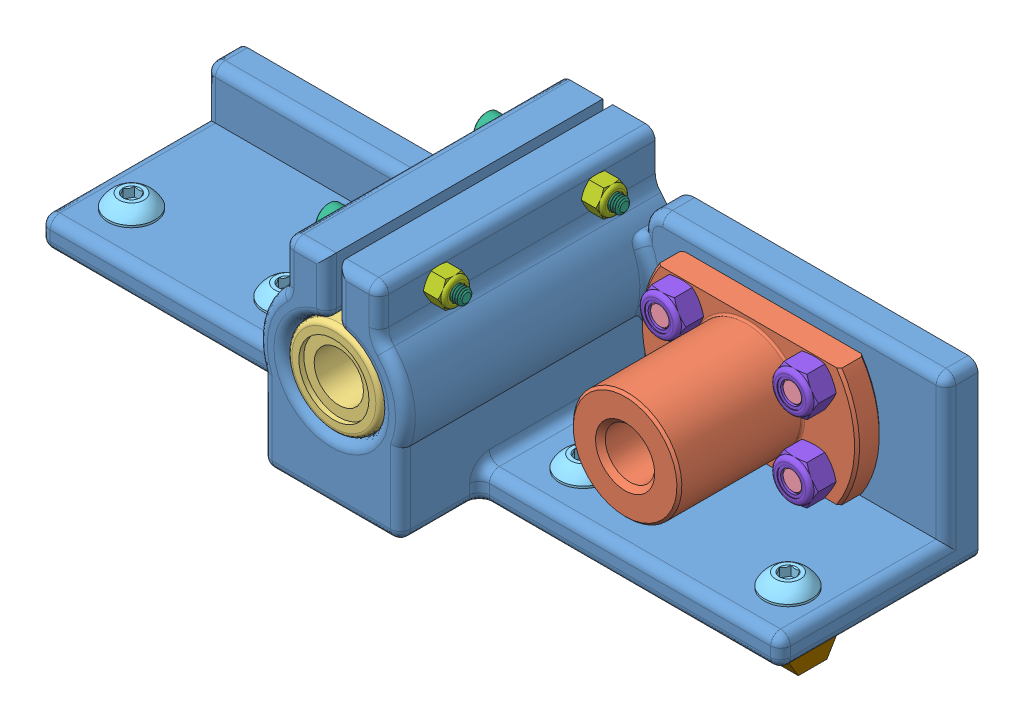
SolidWorks assembly Z_Axis_Bed_Support, configuration Default. Lengths in mm.
Overall size (150 48.5 58.92).
23 component instances, 9 part files, 65 mates.
Components (placement in the parent):
- Z_Axis_Bed_Support-1: Z_Axis_Bed_Support [Default] at origin size (150 43 56)
- MTSGR12-1: MTSGR12 [Default] at (-35 19 6.5) x (0 0 1) z (0 -1 0) size (30 44 24)
- LM10LUU-1: LM10LUU [Default] at (-75 22 0.5) size (19 19 55)
- 5mmX16mm_Buttonhead(McMaster_91239A232)-5: 5mmX16mm_Buttonhead(McMaster_91239A232) [91239A232] at (-48.423 11.25 -2.75) x (0.866025 0.5 0) z (0 0 -1) size (9.5 9.5 19.24)
- 5mmX16mm_Buttonhead(McMaster_91239A232)-7: 5mmX16mm_Buttonhead(McMaster_91239A232) [91239A232] at (-21.577 11.25 -2.75) x (0.866025 0.5 0) z (0 0 -1) size (9.5 9.5 19.24)
- 5mmX16mm_Buttonhead(McMaster_91239A232)-6: 5mmX16mm_Buttonhead(McMaster_91239A232) [91239A232] at (-48.423 26.75 -2.75) x (0.866025 -0.5 0) z (0 0 -1) size (9.5 9.5 19.24)
- 5mmX16mm_Buttonhead(McMaster_91239A232)-4: 5mmX16mm_Buttonhead(McMaster_91239A232) [91239A232] at (-21.577 26.75 -2.75) x (0.866025 -0.5 0) z (0 0 -1) size (9.5 9.5 19.24)
- 5mmX10mm_Buttonhead(McMaster_91239A224)-7: 5mmX10mm_Buttonhead(McMaster_91239A224) [91239A224] at (-8.5 8.75 30) x (0 0 -1) z (0 1 0) size (9.5 9.5 13.21)
- 5mmX10mm_Buttonhead(McMaster_91239A224)-6: 5mmX10mm_Buttonhead(McMaster_91239A224) [91239A224] at (-50 8.75 30) x (0.866025 0 -0.5) z (0 1 0) size (9.5 9.5 13.21)
- 5mmX10mm_Buttonhead(McMaster_91239A224)-8: 5mmX10mm_Buttonhead(McMaster_91239A224) [91239A224] at (-110 8.75 30) x (-0.866025 0 0.5) z (0 1 0) size (9.5 9.5 13.21)
- 5mmX10mm_Buttonhead(McMaster_91239A224)-9: 5mmX10mm_Buttonhead(McMaster_91239A224) [91239A224] at (-141.5 8.75 30) x (-0.866025 0 0.5) z (0 1 0) size (9.5 9.5 13.21)
- 3mmX25mm_Sockethead(McMaster_91290A125)-4: 3mmX25mm_Sockethead(McMaster_91290A125) [91290A125] at (-59.6 38.2628 12) x (0 0 -1) z (1 0 0) size (5.5 5.5 28.26)
- 3mmX25mm_Sockethead(McMaster_91290A125)-3: 3mmX25mm_Sockethead(McMaster_91290A125) [91290A125] at (-59.6 38.2628 44) x (0 0 -1) z (1 0 0) size (5.5 5.5 28.26)
- 3mm_Hex_Nylock_Nut(McMaster_90576A102)-3: 3mm_Hex_Nylock_Nut(McMaster_90576A102) [90576A102] at (-65.4 38.2628 12) x (0 1 0) z (0 0 -1) size (5.5 4.1 6.35)
- 3mm_Hex_Nylock_Nut(McMaster_90576A102)-2: 3mm_Hex_Nylock_Nut(McMaster_90576A102) [90576A102] at (-65.4 38.2628 44) x (0 0.5 0.866025) z (0 0.866025 -0.5) size (5.5 4.1 6.35)
- 5mm_Hex_NyLockNut(McMaster_94205A240)-5: 5mm_Hex_NyLockNut(McMaster_94205A240) [94205A240] at (-21.577 26.75 11.5) x (0.866025 -0.5 0) z (-0.5 -0.866025 0) size (8 5.15 9.24)
- 5mm_Hex_NyLockNut(McMaster_94205A240)-7: 5mm_Hex_NyLockNut(McMaster_94205A240) [94205A240] at (-48.423 26.75 11.5) x (0.866025 -0.5 0) z (-0.5 -0.866025 0) size (8 5.15 9.24)
- 5mm_Hex_NyLockNut(McMaster_94205A240)-6: 5mm_Hex_NyLockNut(McMaster_94205A240) [94205A240] at (-21.577 11.25 11.5) x (0.866025 0.5 0) z (0.5 -0.866025 0) size (8 5.15 9.24)
- 5mm_Hex_NyLockNut(McMaster_94205A240)-4: 5mm_Hex_NyLockNut(McMaster_94205A240) [94205A240] at (-48.423 11.25 11.5) x (-0.866025 -0.5 0) z (-0.5 0.866025 0) size (8 5.15 9.24)
- HNTTSN5-5-1: HNTTSN5-5 [Default] at (-50 -1.2 30) x (0 1 0) z (-1 0 0) size (4.3 10 10)
- HNTTSN5-5-2: HNTTSN5-5 [Default] at (-110 -1.2 30) x (0 1 0) z (1 0 0) size (4.3 10 10)
- HNTTSN5-5-3: HNTTSN5-5 [Default] at (-8.5 -1.2 30) x (0 1 0) z (1 0 0) size (4.3 10 10)
- HNTTSN5-5-4: HNTTSN5-5 [Default] at (-141.5 -1.2 30) x (0 1 0) z (1 0 0) size (4.3 10 10)
Mates (geometry in assembly coordinates):
- Concentric1: concentric aligned: cylinder of Z_Axis_Bed_Support-1 through (-75 22 6.5) axis (0 0 -1) radius 9.65; cylinder of LM10LUU-1 through (-75 22 55.5) axis (0 0 -1) radius 9.5
- Distance1: distance = 0.5 mm aligned: plane of LM10LUU-1 through (-75 22 0.5) normal (0 0 -1); plane of Z_Axis_Bed_Support-1 through (0 6 0) normal (0 0 -1)
- Coincident2: coincident anti-aligned: plane of Z_Axis_Bed_Support-1 through (-57.4 31 6.5) normal (0 0 1); plane of MTSGR12-1 through (-35 19 6.5) normal (0 0 -1)
- Parallel2: parallel aligned: plane of Z_Axis_Bed_Support-1 through (-74 43 6.5) normal (0 1 0); plane of MTSGR12-1 through (9 31 14) normal (0 1 0)
- Concentric4: concentric aligned: cylinder of Z_Axis_Bed_Support-1 through (-35 19 6.5) axis (0 0 -1) radius 7.15; cylinder of MTSGR12-1 through (-35 19 36.5) axis (0 0 -1) radius 5
- Concentric51: concentric aligned: cylinder of Z_Axis_Bed_Support-1 through (-48.423 11.25 6.5) axis (0 0 -1) radius 2.6; cylinder of 5mmX16mm_Buttonhead(McMaster_91239A232)-5 through (-48.423 11.25 -2.75) axis (0 0 -1) radius 4.75
- Coincident31: coincident anti-aligned: plane of Z_Axis_Bed_Support-1 through (0 6 0) normal (0 0 -1); plane of 5mmX16mm_Buttonhead(McMaster_91239A232)-5 through (-50.798 15.3636 0) normal (0 0 1)
- Concentric61: concentric aligned: cylinder of Z_Axis_Bed_Support-1 through (-21.577 11.25 6.5) axis (0 0 -1) radius 2.6; cylinder of 5mmX16mm_Buttonhead(McMaster_91239A232)-7 through (-21.577 11.25 -2.75) axis (0 0 -1) radius 4.75
- Coincident41: coincident anti-aligned: plane of Z_Axis_Bed_Support-1 through (0 6 0) normal (0 0 -1); plane of 5mmX16mm_Buttonhead(McMaster_91239A232)-7 through (-23.952 15.3636 0) normal (0 0 1)
- Concentric71: concentric aligned: cylinder of Z_Axis_Bed_Support-1 through (-48.423 26.75 6.5) axis (0 0 -1) radius 2.6; cylinder of 5mmX16mm_Buttonhead(McMaster_91239A232)-6 through (-48.423 26.75 -2.75) axis (0 0 -1) radius 4.75
- Coincident51: coincident anti-aligned: plane of Z_Axis_Bed_Support-1 through (0 6 0) normal (0 0 -1); plane of 5mmX16mm_Buttonhead(McMaster_91239A232)-6 through (-46.048 30.8636 0) normal (0 0 1)
- Concentric81: concentric aligned: cylinder of Z_Axis_Bed_Support-1 through (-21.577 26.75 6.5) axis (0 0 -1) radius 2.6; cylinder of 5mmX16mm_Buttonhead(McMaster_91239A232)-4 through (-21.577 26.75 -2.75) axis (0 0 -1) radius 4.75
- Coincident61: coincident anti-aligned: plane of Z_Axis_Bed_Support-1 through (0 6 0) normal (0 0 -1); plane of 5mmX16mm_Buttonhead(McMaster_91239A232)-4 through (-19.202 30.8636 0) normal (0 0 1)
- Concentric9: concentric aligned: cylinder of 5mmX16mm_Buttonhead(McMaster_91239A232)-4 through (-21.577 26.75 -2.75) axis (0 0 -1) radius 4.75; cylinder of 5mm_Hex_NyLockNut(McMaster_94205A240)-5 through (-21.577 26.75 15.7429) axis (0 0 -1) radius 2.1277
- Coincident7: coincident anti-aligned: plane of MTSGR12-1 through (-56.5 19 11.5) normal (0 0 1); plane of 5mm_Hex_NyLockNut(McMaster_94205A240)-5 through (-21.577 34.75 11.5) normal (0 0 -1)
- Parallel3: parallel aligned: plane of MTSGR12-1 through (9 31 14) normal (0 1 0); plane of 5mm_Hex_NyLockNut(McMaster_94205A240)-5 through (-19.2676 30.75 16.5) normal (0 1 0)
- Concentric11: concentric aligned: cylinder of 5mmX16mm_Buttonhead(McMaster_91239A232)-7 through (-21.577 11.25 -2.75) axis (0 0 -1) radius 4.75; cylinder of 5mm_Hex_NyLockNut(McMaster_94205A240)-6 through (-21.577 11.25 15.7429) axis (0 0 -1) radius 2.1277
- Coincident9: coincident anti-aligned: plane of MTSGR12-1 through (-56.5 19 11.5) normal (0 0 1); plane of 5mm_Hex_NyLockNut(McMaster_94205A240)-6 through (-28.5052 15.25 11.5) normal (0 0 -1)
- Parallel4: parallel aligned: plane of MTSGR12-1 through (9 31 14) normal (0 1 0); plane of 5mm_Hex_NyLockNut(McMaster_94205A240)-6 through (-19.2676 15.25 16.5) normal (0 1 0)
- Concentric12: concentric aligned: cylinder of 5mmX16mm_Buttonhead(McMaster_91239A232)-6 through (-48.423 26.75 -2.75) axis (0 0 -1) radius 4.75; cylinder of 5mm_Hex_NyLockNut(McMaster_94205A240)-7 through (-48.423 26.75 15.7429) axis (0 0 -1) radius 2.1277
- Coincident11: coincident anti-aligned: plane of MTSGR12-1 through (-56.5 19 11.5) normal (0 0 1); plane of 5mm_Hex_NyLockNut(McMaster_94205A240)-7 through (-48.423 34.75 11.5) normal (0 0 -1)
- Parallel5: parallel aligned: plane of MTSGR12-1 through (9 31 14) normal (0 1 0); plane of 5mm_Hex_NyLockNut(McMaster_94205A240)-7 through (-46.1136 30.75 16.5) normal (0 1 0)
- Concentric13: concentric aligned: cylinder of 5mmX16mm_Buttonhead(McMaster_91239A232)-5 through (-48.423 11.25 -2.75) axis (0 0 -1) radius 4.75; cylinder of 5mm_Hex_NyLockNut(McMaster_94205A240)-4 through (-48.423 11.25 15.7429) axis (0 0 -1) radius 2.1277
- Coincident13: coincident anti-aligned: plane of MTSGR12-1 through (-56.5 19 11.5) normal (0 0 1); plane of 5mm_Hex_NyLockNut(McMaster_94205A240)-4 through (-41.4948 7.25 11.5) normal (0 0 -1)
- Parallel6: parallel aligned: plane of MTSGR12-1 through (9 31 14) normal (0 1 0); plane of 5mm_Hex_NyLockNut(McMaster_94205A240)-4 through (-46.1136 15.25 16.5) normal (0 1 0)
- Parallel7: parallel aligned: plane of 5mmX16mm_Buttonhead(McMaster_91239A232)-5 through (-47.557 9.75 -0.825) normal (0 1 0); plane of Z_Axis_Bed_Support-1 through (-57.4 35 6.5) normal (0 1 0)
- Parallel8: parallel aligned: plane of 5mmX16mm_Buttonhead(McMaster_91239A232)-6 through (-47.557 25.25 -0.825) normal (0 1 0); plane of Z_Axis_Bed_Support-1 through (-57.4 35 6.5) normal (0 1 0)
- Parallel9: parallel aligned: plane of 5mmX16mm_Buttonhead(McMaster_91239A232)-7 through (-20.711 9.75 -0.825) normal (0 1 0); plane of Z_Axis_Bed_Support-1 through (-57.4 35 6.5) normal (0 1 0)
- Parallel10: parallel aligned: plane of 5mmX16mm_Buttonhead(McMaster_91239A232)-4 through (-20.711 25.25 -0.825) normal (0 1 0); plane of Z_Axis_Bed_Support-1 through (-57.4 35 6.5) normal (0 1 0)
- Concentric821: concentric anti-aligned: cylinder of Z_Axis_Bed_Support-1 through (-8.5 6 30) axis (0 -1 0) radius 2.6; cylinder of 5mmX10mm_Buttonhead(McMaster_91239A224)-7 through (-8.5 8.75 30) axis (0 1 0) radius 4.75
- Coincident201: coincident anti-aligned: plane of Z_Axis_Bed_Support-1 through (0 6 0) normal (0 1 0); plane of 5mmX10mm_Buttonhead(McMaster_91239A224)-7 through (-3.75 6 30) normal (0 -1 0)
- Concentric831: concentric anti-aligned: cylinder of Z_Axis_Bed_Support-1 through (-50 6 30) axis (0 -1 0) radius 2.6; cylinder of 5mmX10mm_Buttonhead(McMaster_91239A224)-6 through (-50 8.75 30) axis (0 1 0) radius 4.75
- Coincident211: coincident anti-aligned: plane of Z_Axis_Bed_Support-1 through (0 6 0) normal (0 1 0); plane of 5mmX10mm_Buttonhead(McMaster_91239A224)-6 through (-47.625 6 34.1136) normal (0 -1 0)
- Concentric841: concentric anti-aligned: cylinder of Z_Axis_Bed_Support-1 through (-110 6 30) axis (0 -1 0) radius 2.6; cylinder of 5mmX10mm_Buttonhead(McMaster_91239A224)-8 through (-110 8.75 30) axis (0 1 0) radius 4.75
- Coincident221: coincident anti-aligned: plane of Z_Axis_Bed_Support-1 through (0 6 0) normal (0 1 0); plane of 5mmX10mm_Buttonhead(McMaster_91239A224)-8 through (-112.375 6 25.8864) normal (0 -1 0)
- Concentric851: concentric anti-aligned: cylinder of Z_Axis_Bed_Support-1 through (-141.5 6 30) axis (0 -1 0) radius 2.6; cylinder of 5mmX10mm_Buttonhead(McMaster_91239A224)-9 through (-141.5 8.75 30) axis (0 1 0) radius 4.75
- Coincident231: coincident anti-aligned: plane of Z_Axis_Bed_Support-1 through (0 6 0) normal (0 1 0); plane of 5mmX10mm_Buttonhead(McMaster_91239A224)-9 through (-143.875 6 25.8864) normal (0 -1 0)
- Concentric86: concentric anti-aligned: cylinder of 5mmX10mm_Buttonhead(McMaster_91239A224)-9 through (-141.5 8.75 30) axis (0 1 0) radius 4.75; cylinder of HNTTSN5-5-4 through (-141.5 -1.2 30) axis (0 -1 0) radius 2.067
- Distance2: distance = 2 mm anti-aligned: plane of Z_Axis_Bed_Support-1 through (0 0 0) normal (0 -1 0); plane of HNTTSN5-5-4 through (-136.5 -2 32.9) normal (0 1 0)
- Perpendicular1: perpendicular: plane of Z_Axis_Bed_Support-1 through (0 6 40) normal (0 0 1); plane of HNTTSN5-5-4 through (-146.5 -1.2 30) normal (-1 0 0)
- Concentric87: concentric anti-aligned: cylinder of 5mmX10mm_Buttonhead(McMaster_91239A224)-8 through (-110 8.75 30) axis (0 1 0) radius 4.75; cylinder of HNTTSN5-5-2 through (-110 -1.2 30) axis (0 -1 0) radius 2.067
- Distance3: distance = 2 mm anti-aligned: plane of HNTTSN5-5-2 through (-105 -2 32.9) normal (0 1 0); plane of Z_Axis_Bed_Support-1 through (0 0 0) normal (0 -1 0)
- Perpendicular2: perpendicular: plane of Z_Axis_Bed_Support-1 through (0 6 40) normal (0 0 1); plane of HNTTSN5-5-2 through (-115 -1.2 30) normal (-1 0 0)
- Concentric88: concentric anti-aligned: cylinder of 5mmX10mm_Buttonhead(McMaster_91239A224)-6 through (-50 8.75 30) axis (0 1 0) radius 4.75; cylinder of HNTTSN5-5-1 through (-50 -1.2 30) axis (0 -1 0) radius 2.067
- Distance4: distance = 2 mm anti-aligned: plane of HNTTSN5-5-1 through (-55 -2 27.1) normal (0 1 0); plane of Z_Axis_Bed_Support-1 through (0 0 0) normal (0 -1 0)
- Perpendicular3: perpendicular: plane of Z_Axis_Bed_Support-1 through (0 6 40) normal (0 0 1); plane of HNTTSN5-5-1 through (-55 -1.2 30) normal (-1 0 0)
- Concentric89: concentric anti-aligned: cylinder of 5mmX10mm_Buttonhead(McMaster_91239A224)-7 through (-8.5 8.75 30) axis (0 1 0) radius 4.75; cylinder of HNTTSN5-5-3 through (-8.5 -1.2 30) axis (0 -1 0) radius 2.067
- Perpendicular4: perpendicular: plane of Z_Axis_Bed_Support-1 through (0 6 40) normal (0 0 1); plane of HNTTSN5-5-3 through (-3.5 -1.2 30) normal (1 0 0)
- Distance5: distance = 2 mm anti-aligned: plane of HNTTSN5-5-3 through (-3.5 -2 32.9) normal (0 1 0); plane of Z_Axis_Bed_Support-1 through (0 0 0) normal (0 -1 0)
- Concentric931: concentric anti-aligned: cylinder of Z_Axis_Bed_Support-1 through (-60.8745 38.2628 12) axis (-1 0 0) radius 1.6; cylinder of 3mmX25mm_Sockethead(McMaster_91290A125)-4 through (-84.6 38.2628 12) axis (1 0 0) radius 1.5
- Coincident351: coincident anti-aligned: plane of Z_Axis_Bed_Support-1 through (-84.6 43 6.5) normal (-1 0 0); plane of 3mmX25mm_Sockethead(McMaster_91290A125)-4 through (-84.6 38.2628 12) normal (1 0 0)
- Concentric941: concentric anti-aligned: cylinder of Z_Axis_Bed_Support-1 through (-60.8745 38.2628 44) axis (-1 0 0) radius 1.6; cylinder of 3mmX25mm_Sockethead(McMaster_91290A125)-3 through (-84.6 38.2628 44) axis (1 0 0) radius 1.5
- Coincident361: coincident anti-aligned: plane of Z_Axis_Bed_Support-1 through (-84.6 43 6.5) normal (-1 0 0); plane of 3mmX25mm_Sockethead(McMaster_91290A125)-3 through (-84.6 38.2628 44) normal (1 0 0)
- Parallel13: parallel aligned: plane of Z_Axis_Bed_Support-1 through (-84.6 43 6.5) normal (0 1 0); plane of 3mmX25mm_Sockethead(McMaster_91290A125)-4
- Parallel14: parallel aligned: plane of Z_Axis_Bed_Support-1 through (-84.6 43 6.5) normal (0 1 0); plane of 3mmX25mm_Sockethead(McMaster_91290A125)-3
- Concentric951: concentric aligned: cylinder of Z_Axis_Bed_Support-1 through (-60.8745 38.2628 12) axis (-1 0 0) radius 1.6; cylinder of 3mm_Hex_Nylock_Nut(McMaster_90576A102)-3 through (-61.9905 38.2628 12) axis (-1 0 0) radius 1.269
- Coincident411: coincident anti-aligned: plane of Z_Axis_Bed_Support-1 through (-65.4 43 6.5) normal (1 0 0); plane of 3mm_Hex_Nylock_Nut(McMaster_90576A102)-3 through (-65.4 38.2628 15.1754) normal (-1 0 0)
- Concentric961: concentric aligned: cylinder of Z_Axis_Bed_Support-1 through (-60.8745 38.2628 44) axis (-1 0 0) radius 1.6; cylinder of 3mm_Hex_Nylock_Nut(McMaster_90576A102)-2 through (-61.9905 38.2628 44) axis (-1 0 0) radius 1.269
- Coincident421: coincident anti-aligned: plane of Z_Axis_Bed_Support-1 through (-65.4 43 6.5) normal (1 0 0); plane of 3mm_Hex_Nylock_Nut(McMaster_90576A102)-2 through (-65.4 35.5128 45.5877) normal (-1 0 0)
- Parallel15: parallel aligned: plane of Z_Axis_Bed_Support-1 through (-74 43 6.5) normal (0 1 0); plane of 3mm_Hex_Nylock_Nut(McMaster_90576A102)-3 through (-61.4 41.0128 10.4123) normal (0 1 0)
- Parallel16: parallel aligned: plane of Z_Axis_Bed_Support-1 through (-74 43 6.5) normal (0 1 0); plane of 3mm_Hex_Nylock_Nut(McMaster_90576A102)-2 through (-61.4 41.0128 42.4123) normal (0 1 0)
- Parallel17: parallel aligned: plane of Z_Axis_Bed_Support-1 through (0 6 0) normal (0 0 -1); plane of 5mmX10mm_Buttonhead(McMaster_91239A224)-9 through (-142.366 6.825 31.5) normal (0 0 -1)
- Parallel18: parallel aligned: plane of Z_Axis_Bed_Support-1 through (0 6 0) normal (0 0 -1); plane of 5mmX10mm_Buttonhead(McMaster_91239A224)-8 through (-110.866 6.825 31.5) normal (0 0 -1)
- Parallel19: parallel aligned: plane of Z_Axis_Bed_Support-1 through (0 6 0) normal (0 0 -1); plane of 5mmX10mm_Buttonhead(McMaster_91239A224)-6 through (-50.866 6.825 31.5) normal (0 0 -1)
- Parallel20: parallel aligned: plane of Z_Axis_Bed_Support-1 through (0 6 0) normal (0 0 -1); plane of 5mmX10mm_Buttonhead(McMaster_91239A224)-7 through (-9.366 6.825 31.5) normal (0 0 -1)
